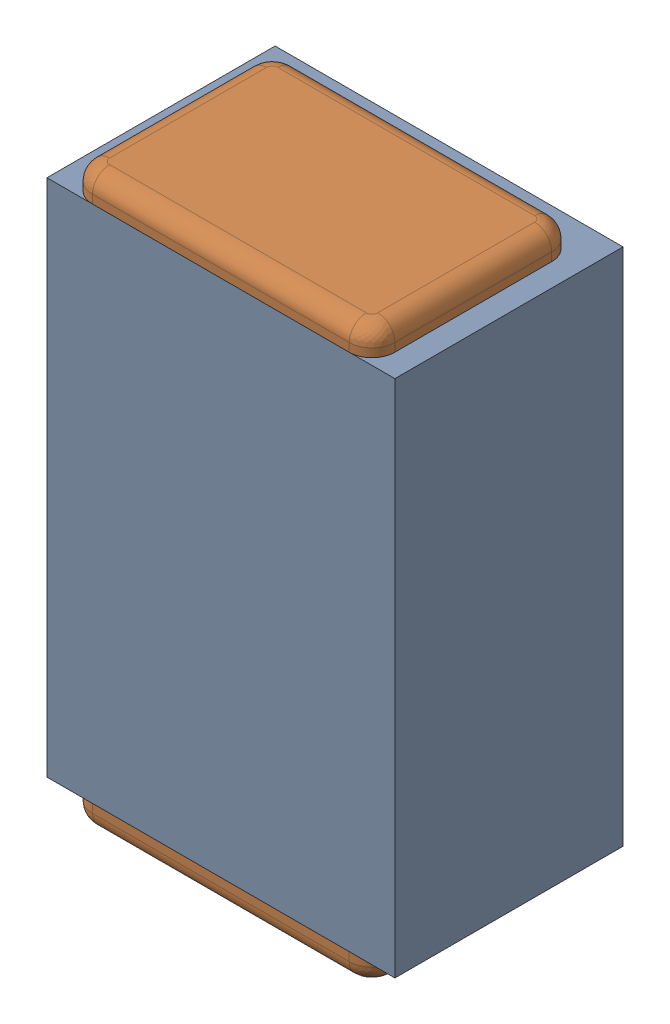
SolidWorks assembly C24, configuration Default. Lengths in mm.
Overall size (0.61 1 0.4).
3 component instances, 2 part files, 0 mates.
Components (placement in the parent):
- 1088881848-1: 1088881848 [Default] at (7.575 44.225 -2.044) size (0.61 0.91 0.4)
  - Extruded-1-1: Extruded-1 [Default] at origin size (0.61 0.91 0.4)
- C0402-1: C0402 [Default] at (7.5749 44.2249 -1.644) x (0 -1 0) z (1 0 0) size (1 0.36 0.54)
